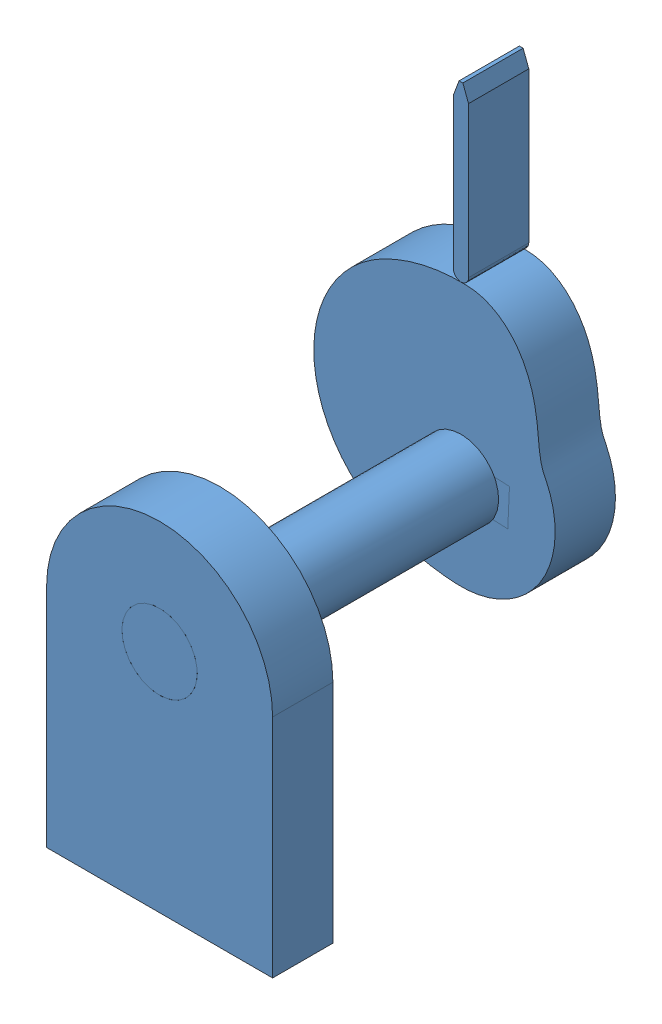
SolidWorks assembly Ensamble_Leva, configuration Default. Lengths in mm.
Overall size (375 978.47 480).
4 component instances, 1 part files, 7 mates.
Components (placement in the parent):
- Leva_2-1: Leva_2 [Soporte] at (155.9619 263.6656 402.9067) size (375 450 80)
- Leva_2-2: Leva_2 [Eje] at (155.9619 263.6656 42.9067) x (-0.044476 -0.99901 0) z (0 0 1) size (350 322.5 480)
- Leva_2-3: Leva_2 [Leva] at (155.9619 263.6656 2.9067) x (-0.044476 -0.99901 0) z (0 0 1) size (350 322.5 80)
- Leva_2-4: Leva_2 [Seguidor] at (155.9619 498.6656 -37.0933) size (375 743.47 80)
Mates (geometry in assembly coordinates):
- Concéntrica2: concentric aligned: circle of Leva_2-1; circle of Leva_2-2
- Coincidente5: coincident aligned: plane of Leva_2-1 through (155.9619 263.6656 442.9067) normal (0 0 1); plane of Leva_2-2 through (155.9619 263.6656 442.9067) normal (0 0 1)
- Coincidente11: coincident aligned: circle of Leva_2-2; circle of Leva_2-3
- Coincidente12: coincident anti-aligned: line of Leva_2-2 through (220.3124 285.8255 -37.0933) axis (-0.044476 -0.99901 0); line of Leva_2-3 through (218.0886 235.875 -37.0933) axis (0.044476 0.99901 0)
- Coincidente22: coincident: plane of Leva_2-1 through (155.9619 263.6656 402.9067) normal (1 0 0); line of Leva_2-4 through (155.9619 543.4076 -37.0933) axis (0 1 0)
- Coincidente24: coincident aligned: plane of Leva_2-3 through (109.3927 483.7935 -37.0933) normal (0 0 -1); plane of Leva_2-4 through (155.9619 543.4076 -37.0933) normal (0 0 -1)
- Tangente2: tangent: face of Leva_2-3; cylinder of Leva_2-4 through (155.9619 498.6656 42.9067) axis (0 0 -1) radius 10
